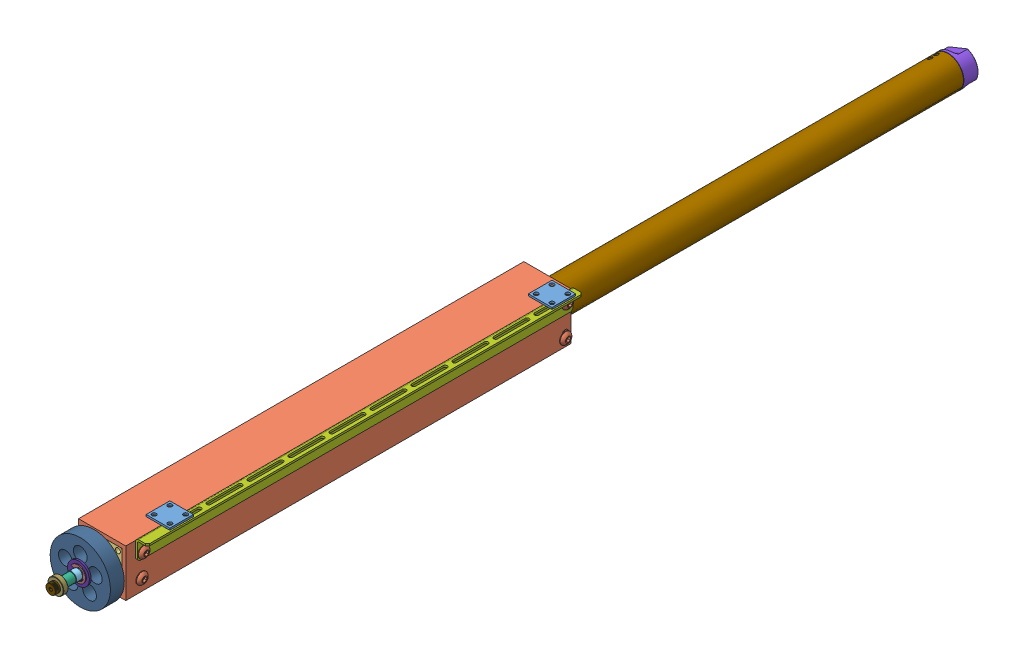
SolidWorks assembly DART 12 Lead Screw Module, configuration Default. Lengths in mm.
Overall size (52.77 48.51 734.7).
33 component instances, 20 part files, 4 mates.
Components (placement in the parent):
- am-3260 Spacer-1: am-3260 Spacer [Default] at (-12.1808 -37.53 -73.8188) x (-0.979015 0.203789 0) z (0 0 1) size (12.7 12.7 6.35)
- am-3260 Spacer-2: am-3260 Spacer [Default] at (-12.1808 -37.53 -51.4667) x (0.189554 -0.98187 0) z (0 0 -1) size (12.7 12.7 6.35)
- am-3254 DART 12 Square Tube Rev1-1-1: am-3254 DART 12 Square Tube Rev1-1 [Default] at (-31.2943 -56.58 -416.7188) size (38.1 38.1 358.78)
- am-3253 DART Bearing Block-1: am-3253 DART Bearing Block [Default] at (3.6307 -53.3415 -57.9438) x (-1 0 0) z (0 0 -1) size (31.62 31.62 25.4)
- am-3259 DART Ram End Bearing-1: am-3259 DART Ram End Bearing [Default] at (-27.9923 -21.7185 -416.7188) x (0 -1 0) z (0 0 1) size (31.62 31.62 9.53)
- am-3257 DART 12 Lead Screw-1: am-3257 DART 12 Lead Screw [Default] at (-12.1808 -37.53 -416.4457) x (0 0 1) z (-1 0 0) size (380.17 12.7 12.7)
- am-3268 Gear, 14T, 48dp, Steel-1: am-3268 Gear, 14T, 48dp, Steel [Default] at (-12.1808 -37.53 -24.2126) x (1 0 0) z (0 1 0) size (7.41 8.89 7.41)
- am-3252 DART 12 Sensor Bracket-1: am-3252 DART 12 Sensor Bracket [Default] at (6.8057 -19.2039 -416.7188) x (0 0 1) z (0 1 0) size (350.84 9.53 15.88)
- am-3258 DART Ram Cap-1: am-3258 DART Ram Cap [Default] at (-12.1808 -37.53 -750.9955) x (0 0 1) z (-0.926565 -0.376134 0) size (24.59 25.4 25.4)
- am-3256 DART Ram 12 Tube-1: am-3256 DART Ram 12 Tube [Default] at (-12.1808 -37.53 -739.1082) x (0.926565 0.376134 0) z (0 0 1) size (25.4 25.4 334.96)
- am-3265 30T Pulley-1: am-3265 30T Pulley [Default] at (-12.1808 -37.53 -51.4667) x (1 0 0) z (0 -1 0) size (48.51 11.18 48.51)
- am-1121-1: am-1121 [Default] at (-13.1648 -34.5262 -50.2908) size (2 2 10)
- R3 Bearing-1: R3 Bearing [Default] at (-12.1808 -37.53 -24.2888) size (12.7 12.7 3.89)
- Retaining Ring 3125_97431A310-1: Retaining Ring 3125_97431A310 [Default] at (-12.1808 -37.53 -408.6352) x (0 0 1) z (-0.983883 -0.178816 0) size (0.64 12.7 11.58)
- Retaining Ring 3125_97431A310-2: Retaining Ring 3125_97431A310 [Default] at (-12.1808 -37.53 -38.5001) x (0 0 1) z (-1 0 0) size (0.64 12.7 11.58)
- am-3255 DART Back Bearing-1: am-3255 DART Back Bearing [Default] at (3.6307 -21.7185 -89.8208) x (0 -1 0) z (1 0 0) size (31.63 9.53 31.62)
- am-3262 DART Nut-1: am-3262 DART Nut [Default] at (-12.1808 -37.53 -54.3758) size (28.45 28.45 19.05)
- 1614Z Bearing_smart-1: 1614Z Bearing_smart [Default] at (-12.1808 -37.53 -83.4707) x (0 0 1) z (-1 0 0) size (9.65 28.7 28.7)
- 1614Z Bearing_smart-2: 1614Z Bearing_smart [Default] at (-12.1808 -37.53 -67.4688) x (0 0 1) z (-1 0 0) size (9.65 28.7 28.7)
- 5-16 washer_1-1: 5-16 washer_1 [Default] at (-12.1808 -37.53 -40.2908) size (17.53 17.53 1.47)
- 5-16 washer_1-2: 5-16 washer_1 [Default] at (-12.1808 -37.53 -408.3939) size (17.53 17.53 1.47)
- 1875 dia 500 long 8-32_91259A166-1: 1875 dia 500 long 8-32_91259A166 [Default] at (-12.1808 -37.53 -20.4025) x (1 0 0) z (0 -1 0) size (7.94 21.71 7.94)
- Hall Effect Sensor-1: Hall Effect Sensor [Default] at (-3.8623 -15.3685 -85.0583) x (0 0 -1) z (-1 0 0) size (19.05 2.79 19.05)
- am-3255 DART Back Bearing-2: am-3255 DART Back Bearing [Default] at (3.6307 -21.7185 -397.6687) x (0 -1 0) z (1 0 0) size (31.63 9.53 31.62)
- Hall Effect Sensor-2: Hall Effect Sensor [Default] at (-3.8623 -15.3685 -392.9062) x (0 0 -1) z (-1 0 0) size (19.05 2.79 19.05)
- BHCS 10-32 x 0.375 phillips_SBHCSCREW 0.19-32x0.5-HX-C-1: BHCS 10-32 x 0.375 phillips_SBHCSCREW 0.19-32x0.5-HX-C [Default] at (9.3711 -47.055 -70.6438) x (-1 0 0) z (0 -0.924225 -0.381849) size (12.6 9.29 9.24)
- BHCS 10-32 x 0.375 phillips_SBHCSCREW 0.19-32x0.5-HX-C-2: BHCS 10-32 x 0.375 phillips_SBHCSCREW 0.19-32x0.5-HX-C [Default] at (9.3711 -50.23 -411.9563) x (-1 0 0) z (0 -0.924225 -0.381849) size (12.6 9.29 9.24)
- BHCS 10-32 x 0.375 phillips_SBHCSCREW 0.19-32x0.5-HX-C-3: BHCS 10-32 x 0.375 phillips_SBHCSCREW 0.19-32x0.5-HX-C [Default] at (10.8951 -28.005 -70.6438) x (-1 0 0) z (0 -0.924225 -0.381849) size (12.6 9.29 9.24)
- BHCS 10-32 x 0.375 phillips_SBHCSCREW 0.19-32x0.5-HX-C-4: BHCS 10-32 x 0.375 phillips_SBHCSCREW 0.19-32x0.5-HX-C [Default] at (10.8951 -24.83 -411.9563) x (-1 0 0) z (0 -0.924225 -0.381849) size (12.6 9.29 9.24)
- BHCS 10-32 x 0.375 phillips_SBHCSCREW 0.19-32x0.5-HX-C-5: BHCS 10-32 x 0.375 phillips_SBHCSCREW 0.19-32x0.5-HX-C [Default] at (-33.8597 -50.23 -411.9563) size (12.6 9.29 9.24)
- BHCS 10-32 x 0.375 phillips_SBHCSCREW 0.19-32x0.5-HX-C-6: BHCS 10-32 x 0.375 phillips_SBHCSCREW 0.19-32x0.5-HX-C [Default] at (-33.8597 -24.83 -411.9563) size (12.6 9.29 9.24)
- BHCS 10-32 x 0.375 phillips_SBHCSCREW 0.19-32x0.5-HX-C-7: BHCS 10-32 x 0.375 phillips_SBHCSCREW 0.19-32x0.5-HX-C [Default] at (-33.8597 -28.005 -70.6438) size (12.6 9.29 9.24)
- BHCS 10-32 x 0.375 phillips_SBHCSCREW 0.19-32x0.5-HX-C-8: BHCS 10-32 x 0.375 phillips_SBHCSCREW 0.19-32x0.5-HX-C [Default] at (-33.8597 -47.055 -70.6438) size (12.6 9.29 9.24)
Mates (geometry in assembly coordinates):
- Concentric1: concentric aligned: cylinder of am-3258 DART Ram Cap-1 through (-12.1808 -37.53 -726.4082) axis (0 0 -1) radius 11.0998; cylinder of am-3256 DART Ram 12 Tube-1 through (-12.1808 -37.53 -739.1082) axis (0 0 -1) radius 11.1125
- Concentric2: concentric aligned: cylinder of am-3258 DART Ram Cap-1 through (-7.4039 -49.2974 -729.5833) axis (-0.376134 0.926565 0) radius 1.5875; cylinder of am-3256 DART Ram 12 Tube-1 through (-7.4039 -49.2974 -729.5833) axis (-0.376134 0.926565 0) radius 1.5875
- Concentric3: concentric aligned: cylinder of am-3259 DART Ram End Bearing-1 through (-12.1808 -37.53 -407.1938) axis (0 0 1) radius 12.7254; cylinder of am-3256 DART Ram 12 Tube-1 through (-12.1808 -37.53 -739.1082) axis (0 0 1) radius 12.7
- LimitDistance1: limit distance = 304.8 mm anti-aligned: plane of am-3256 DART Ram 12 Tube-1 through (-12.1808 -37.53 -404.1458) normal (0 0 1); plane of am-3255 DART Back Bearing-1 through (3.6307 -21.7185 -99.3457) normal (0 0 -1)
